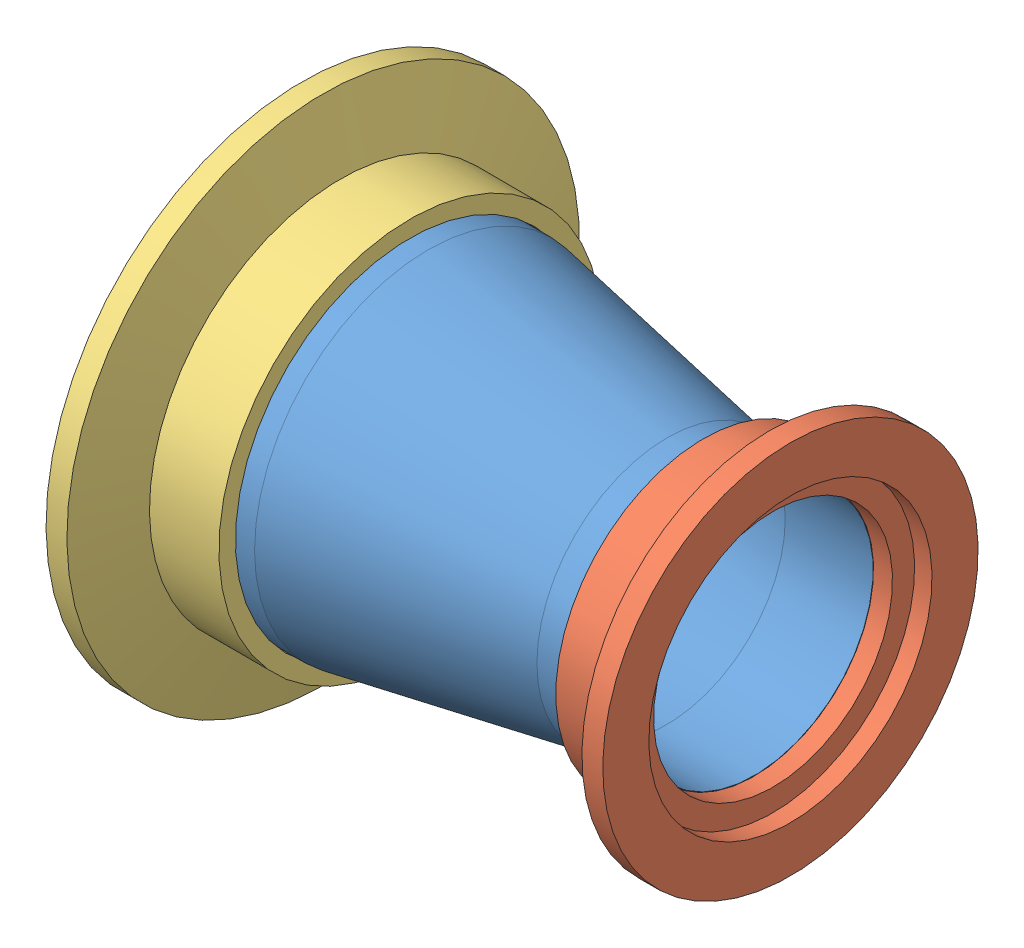
SolidWorks assembly 732009, configuration Default. Lengths in mm.
Overall size (71.35 89.76 89.76).
3 component instances, 3 part files, 4 mates.
Components (placement in the parent):
- 402504-1: 402504 [Default] at (-5.9683 33.3183 44.1716) size (60.32 50.8 50.8)
- 713003-1: 713003 [Default] at (59.6653 33.3183 44.1716) x (0 -0.173312 -0.984867) z (0 -0.984867 0.173312) size (54.86 12.7 54.86)
- 713004-1: 713004 [Default] at (-11.6833 33.3183 44.1716) x (0 0.974804 -0.223062) z (0 0.223062 0.974804) size (74.93 15.75 74.93)
Mates (geometry in assembly coordinates):
- Concentric1: concentric anti-aligned: cylinder of 402504-1 through (-5.9683 33.3183 44.1716) axis (-1 0 0) radius 19.05; cylinder of 713003-1 through (59.6653 33.3183 44.1716) axis (1 0 0) radius 19.177
- Coincident1: coincident anti-aligned: plane of 402504-1 through (54.3567 52.3683 44.1716) normal (1 0 0); plane of 713003-1 through (54.3567 29.9947 25.2848) normal (-1 0 0)
- Coincident2: coincident anti-aligned: plane of 402504-1 through (-5.9683 33.3183 44.1716) normal (-1 0 0); plane of 713004-1 through (-5.9683 58.2022 38.4775) normal (1 0 0)
- Concentric2: concentric aligned: cylinder of 402504-1 through (-5.9683 33.3183 44.1716) axis (-1 0 0) radius 25.4; cylinder of 713004-1 through (-11.6833 33.3183 44.1716) axis (-1 0 0) radius 27.94
